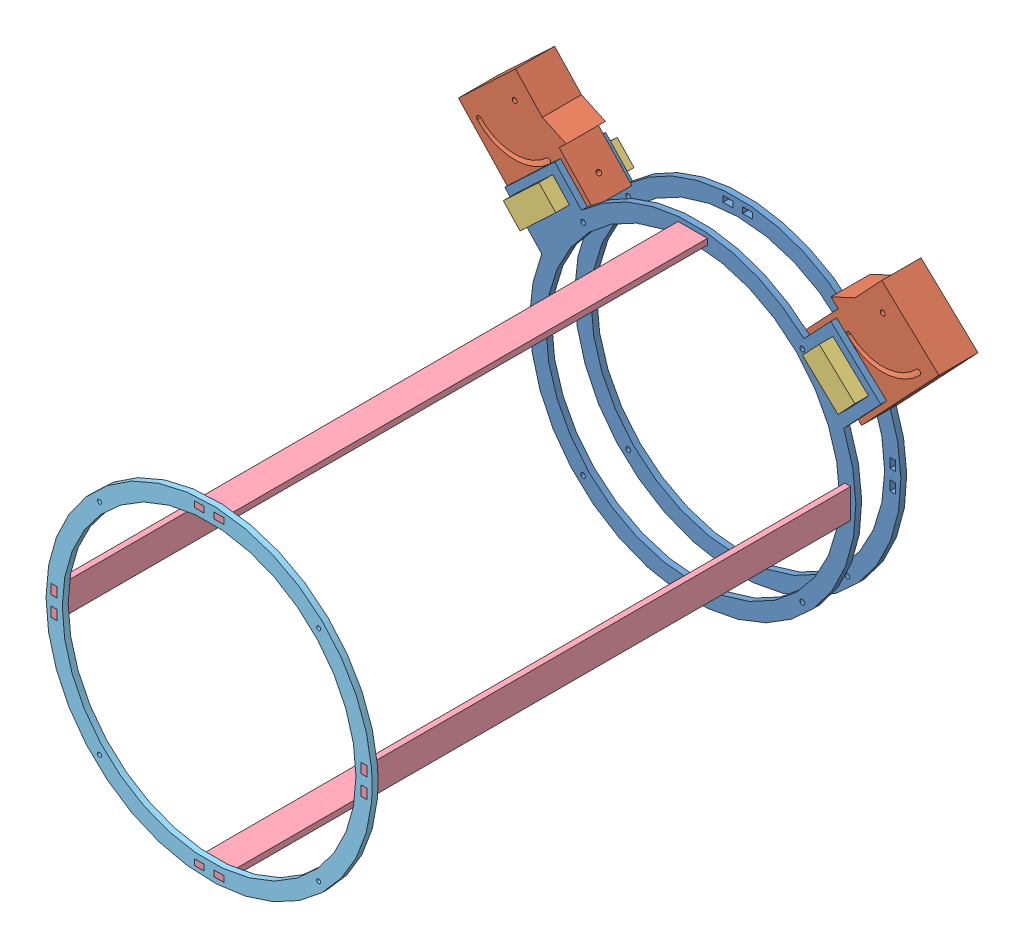
SolidWorks assembly Armado final_2, configuration Predeterminado. Lengths in mm.
Overall size (490.65 380.63 560.02).
12 component instances, 5 part files, 18 mates.
Components (placement in the parent):
- Aramado-1: Aramado [Predeterminado] at (-348.9554 21.8342 490.6527) size (490.65 380.63 80.02)
  - Anillo acrilico-1: Anillo acrilico [Predeterminado] at (-159.8874 164.786 383.9345) size (383.93 333.2 6)
  - anclaje para base_1-3: anclaje para base_1 [Predeterminado] at (-195.9783 155.136 343.9345) x (0 0 -1) z (-0.685795 0.727795 0) size (40 90 115)
  - Anillo acrilico-2: Anillo acrilico [Predeterminado] at (-159.8874 164.786 337.9345) size (383.93 333.2 6)
  - anclaje para base_1-4: anclaje para base_1 [Predeterminado] at (184.5852 155.136 383.9345) x (0 0 1) z (0.685795 0.727795 0) size (40 90 115)
  - Pieza prisionera-1: Pieza prisionera [Predeterminado] at (-166.2782 137.2738 323.9284) x (-0.685795 0.727795 0) z (0 0 1) size (25 50 80)
  - Pieza prisionera-2: Pieza prisionera [Predeterminado] at (165.5199 127.2527 323.9108) x (0.685795 0.727795 0) z (0 0 1) size (25 50 80)
- Barra anillo acrilico-1: Barra anillo acrilico [Predeterminado] at (-346.1008 189.0491 945.792) x (0 0 1) z (0 -1 0) size (500 30 6)
- Barra anillo acrilico-2: Barra anillo acrilico [Predeterminado] at (-509.9512 19.1987 945.792) x (0 0 1) z (-1 0 0) size (500 30 6)
- Barra anillo acrilico-3: Barra anillo acrilico [Predeterminado] at (-346.1008 -127.5494 945.792) x (0 0 1) z (0 -1 0) size (500 30 6)
- Barra anillo acrilico-4: Barra anillo acrilico [Predeterminado] at (-193.3527 19.1987 945.792) x (0 0 1) z (-1 0 0) size (500 30 6)
- Anillo acrilico intermedio-1: Anillo acrilico intermedio [Predeterminado] at (-508.8427 186.6202 1368.5873) size (333.2 333.2 6)
Mates (geometry in assembly coordinates):
- Coincidente6: coincident aligned: line of Aramado-1/Anillo acrilico-1 through (-349.6519 183.0491 874.5873) axis (1 0 0); line of Barra anillo acrilico-1 through (-349.6519 183.0491 874.5873) axis (1 0 0)
- Coincidente7: coincident aligned: plane of Aramado-1/Anillo acrilico-1 through (-508.8427 186.6202 874.5873) normal (0 0 -1); plane of Barra anillo acrilico-1 through (-346.1008 183.0491 874.5873) normal (0 0 -1)
- Coincidente8: coincident anti-aligned: plane of Aramado-1/Anillo acrilico-1 through (-508.8427 183.0491 870.5873) normal (0 1 0); plane of Barra anillo acrilico-1 through (-346.1008 183.0491 945.792) normal (0 -1 0)
- Coincidente9: coincident anti-aligned: plane of Aramado-1/Anillo acrilico-1 through (-339.6519 186.6202 870.5873) normal (-1 0 0); plane of Barra anillo acrilico-1 through (-339.6519 183.0491 945.792) normal (1 0 0)
- Coincidente11: coincident aligned: plane of Aramado-1/Anillo acrilico-1 through (-508.8427 186.6202 874.5873) normal (0 0 -1); plane of Barra anillo acrilico-2 through (-515.9512 19.1987 874.5873) normal (0 0 -1)
- Coincidente12: coincident anti-aligned: plane of Aramado-1/Anillo acrilico-1 through (-508.8427 42.7499 870.5873) normal (0 -1 0); plane of Barra anillo acrilico-2 through (-515.9512 42.7499 945.792) normal (0 1 0)
- Coincidente13: coincident anti-aligned: plane of Aramado-1/Anillo acrilico-1 through (-515.9512 186.6202 870.5873) normal (1 0 0); plane of Barra anillo acrilico-2 through (-515.9512 19.1987 945.792) normal (-1 0 0)
- Coincidente14: coincident aligned: plane of Aramado-1/Anillo acrilico-1 through (-508.8427 186.6202 874.5873) normal (0 0 -1); plane of Barra anillo acrilico-4 through (-199.3527 19.1987 874.5873) normal (0 0 -1)
- Coincidente15: coincident anti-aligned: plane of Aramado-1/Anillo acrilico-1 through (-199.3527 186.6202 870.5873) normal (1 0 0); plane of Barra anillo acrilico-4 through (-199.3527 19.1987 945.792) normal (-1 0 0)
- Coincidente16: coincident anti-aligned: plane of Aramado-1/Anillo acrilico-1 through (-508.8427 42.7499 870.5873) normal (0 -1 0); plane of Barra anillo acrilico-4 through (-199.3527 42.7499 945.792) normal (0 1 0)
- Coincidente17: coincident aligned: plane of Aramado-1/Anillo acrilico-1 through (-508.8427 186.6202 874.5873) normal (0 0 -1); plane of Barra anillo acrilico-3 through (-346.1008 -133.5494 874.5873) normal (0 0 -1)
- Coincidente18: coincident anti-aligned: plane of Aramado-1/Anillo acrilico-1 through (-508.8427 -133.5494 870.5873) normal (0 1 0); plane of Barra anillo acrilico-3 through (-346.1008 -133.5494 945.792) normal (0 -1 0)
- Coincidente19: coincident anti-aligned: plane of Aramado-1/Anillo acrilico-1 through (-369.6519 186.6202 870.5873) normal (1 0 0); plane of Barra anillo acrilico-3 through (-369.6519 -133.5494 945.792) normal (-1 0 0)
- Coincidente20: coincident aligned: plane of Barra anillo acrilico-1 through (-346.1008 183.0491 1374.5873) normal (0 0 1); plane of Anillo acrilico intermedio-1 through (-508.8427 186.6202 1374.5873) normal (0 0 1)
- Coincidente21: coincident anti-aligned: plane of Barra anillo acrilico-1 through (-346.1008 183.0491 945.792) normal (0 -1 0); plane of Anillo acrilico intermedio-1 through (-508.8427 183.0491 1364.5873) normal (0 1 0)
- Coincidente22: coincident anti-aligned: plane of Barra anillo acrilico-1 through (-346.1008 189.0491 945.792) normal (0 1 0); plane of Anillo acrilico intermedio-1 through (-508.8427 189.0491 1364.5873) normal (0 -1 0)
- Coincidente23: coincident anti-aligned: line of Barra anillo acrilico-1 through (-339.6519 183.0491 1374.5873) axis (-1 0 0); line of Anillo acrilico intermedio-1 through (-349.6519 183.0491 1374.5873) axis (1 0 0)
- Coincidente24: coincident anti-aligned: plane of Barra anillo acrilico-1 through (-339.6519 183.0491 945.792) normal (1 0 0); plane of Anillo acrilico intermedio-1 through (-339.6519 186.6202 1364.5873) normal (-1 0 0)
